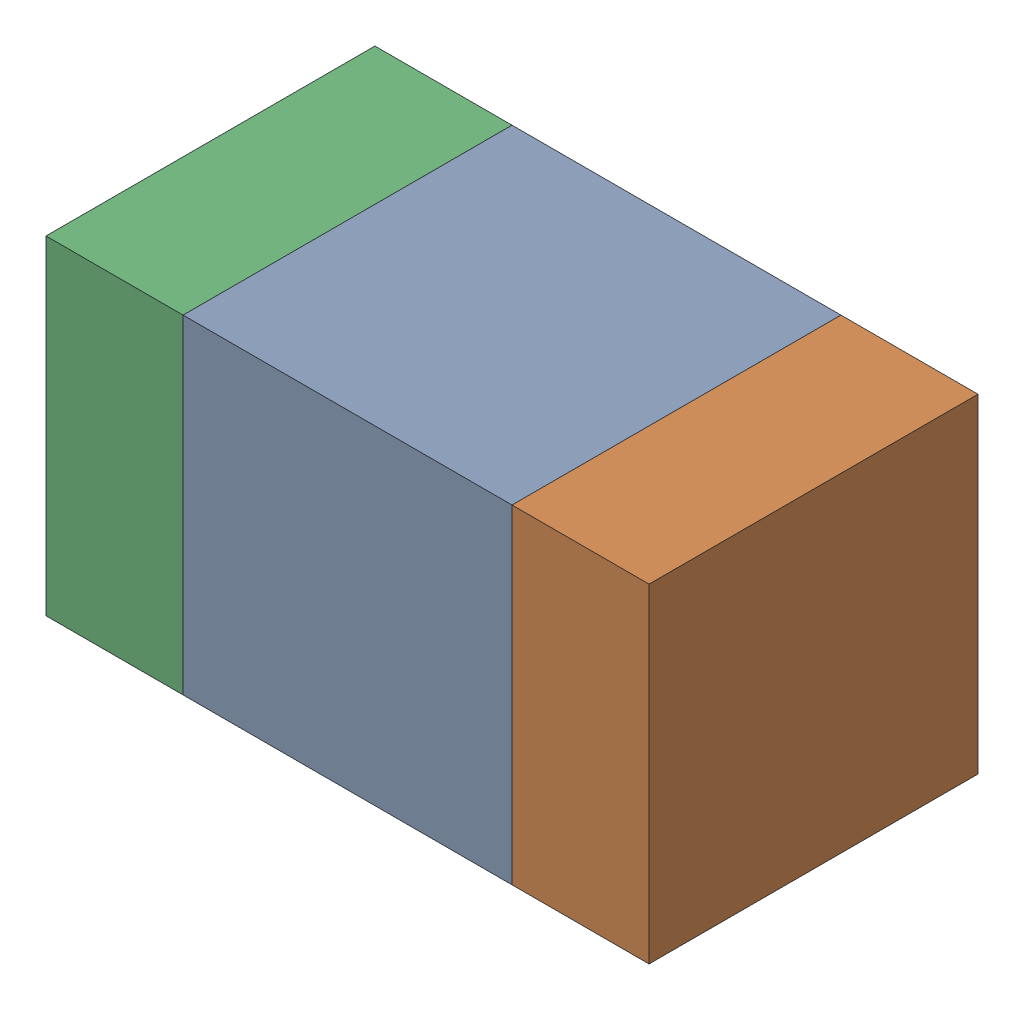
SolidWorks assembly C126_1PCB, configuration Default. Lengths in mm.
Overall size (1.1 0.6 0.6).
6 component instances, 2 part files, 0 mates.
Components (placement in the parent):
- 761606048-1: 761606048 [Default] at (105.8 105.4 0) size (0.6 0.6 0.6)
  - Extruded_9-1: Extruded_9 [Default] at origin size (0.6 0.6 0.6)
- 854785160-1: 854785160 [Default] at (106.225 105.4 0) size (0.25 0.6 0.6)
  - Extruded_19-1: Extruded_19 [Default] at origin size (0.25 0.6 0.6)
- 854785160-2: 854785160 [Default] at (105.375 105.4 0) size (0.25 0.6 0.6)
  - Extruded_19-1: Extruded_19 [Default] at origin size (0.25 0.6 0.6)
